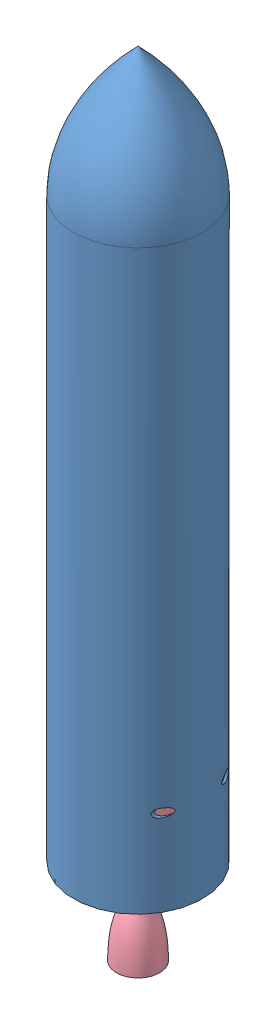
SolidWorks assembly Rocket, configuration Default. Lengths in mm.
Overall size (321.7 1838.77 321.7).
4 component instances, 4 part files, 4 mates.
Components (placement in the parent):
- Shell-1: Shell [Default] at (702.6628 425.012 1503.7868) size (300 1640 300)
- LOXTank-1: LOXTank [Default] at (583.5027 849.9796 1541.5473) x (0.953281 0 -0.302084) z (0.302084 0 0.953281) size (250 440 250)
- FuelTank-1: FuelTank [Default] at (658.8996 1291.5966 1620.8756) x (0.350106 0 -0.93671) z (0.93671 0 0.350106) size (250 600 250)
- Engine-1: Engine [Default] at (652.6628 426.2469 1503.7868) size (200 500 200)
Mates (geometry in assembly coordinates):
- Concentric1: concentric anti-aligned: cylinder of Shell-1 through (702.6628 425.012 1503.7868) axis (0 -1 0) radius 145; cylinder of LOXTank-1 through (702.6628 1164.9796 1503.7868) axis (0 1 0) radius 125
- Concentric2: concentric anti-aligned: cylinder of Shell-1 through (702.6628 425.012 1503.7868) axis (0 -1 0) radius 145; cylinder of FuelTank-1 through (702.6628 1766.5966 1503.7868) axis (0 1 0) radius 125
- Concentric3: concentric aligned: cylinder of Shell-1 through (702.6628 425.012 1503.7868) axis (0 -1 0) radius 145; cylinder of Engine-1 through (702.6628 226.2469 1503.7868) axis (0 -1 0) radius 50
- Parallel1: parallel aligned: plane of Engine-1 through (802.6628 726.2469 1603.7868) normal (0 0 1)
